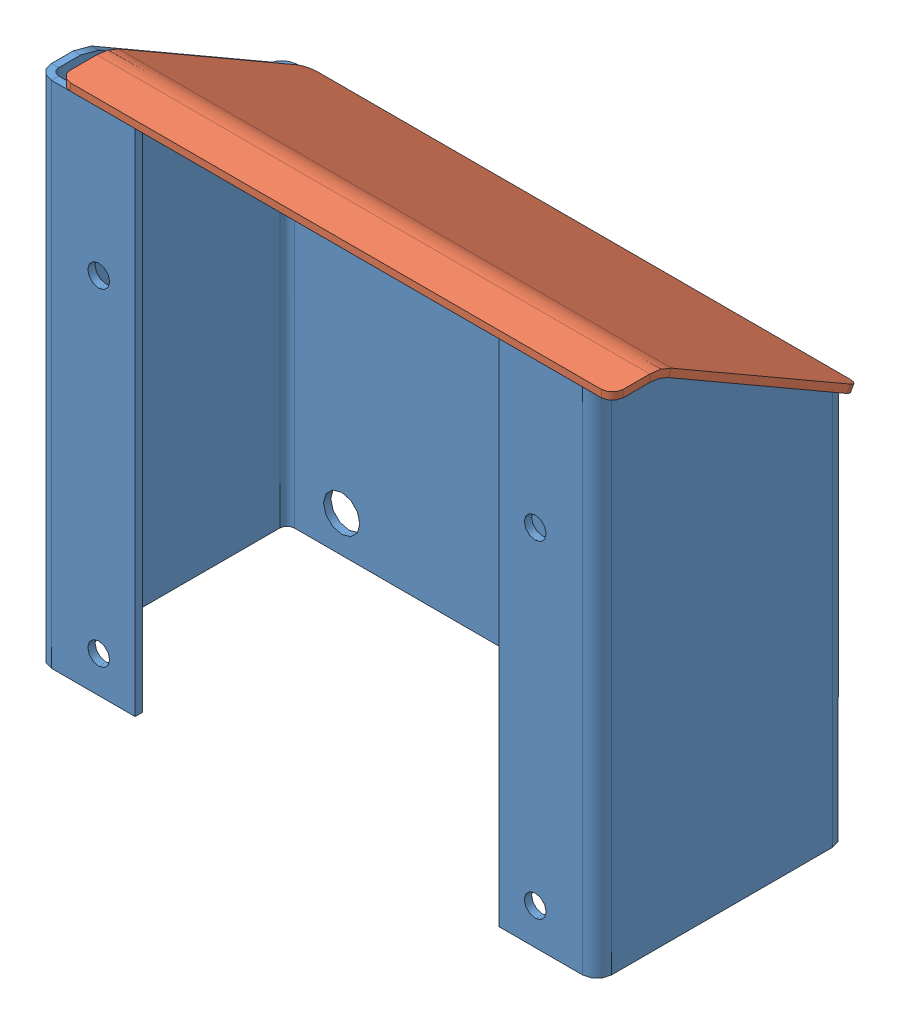
SolidWorks assembly Assem1, configuration Default. Lengths in mm.
Overall size (158.18 142 68.79).
2 component instances, 2 part files, 1 mates.
Components (placement in the parent):
- 53 570 - 2cast-1: 53 570 - 2cast [Default] at origin size (154 140 68.79)
- 53 570 - 1cast-1: 53 570 - 1cast [Default] at (158.1771 31.2397 53.7883) x (0 0 1) z (-1 0 0) size (68.13 33.25 152)
Mates (geometry in assembly coordinates):
- Coincident2: coincident anti-aligned: line of 53 570 - 2cast-1 through (27 31.2397 66.7883) axis (-1 0 0); line of 53 570 - 1cast-1 through (9.1771 31.2397 66.7883) axis (1 0 0)
